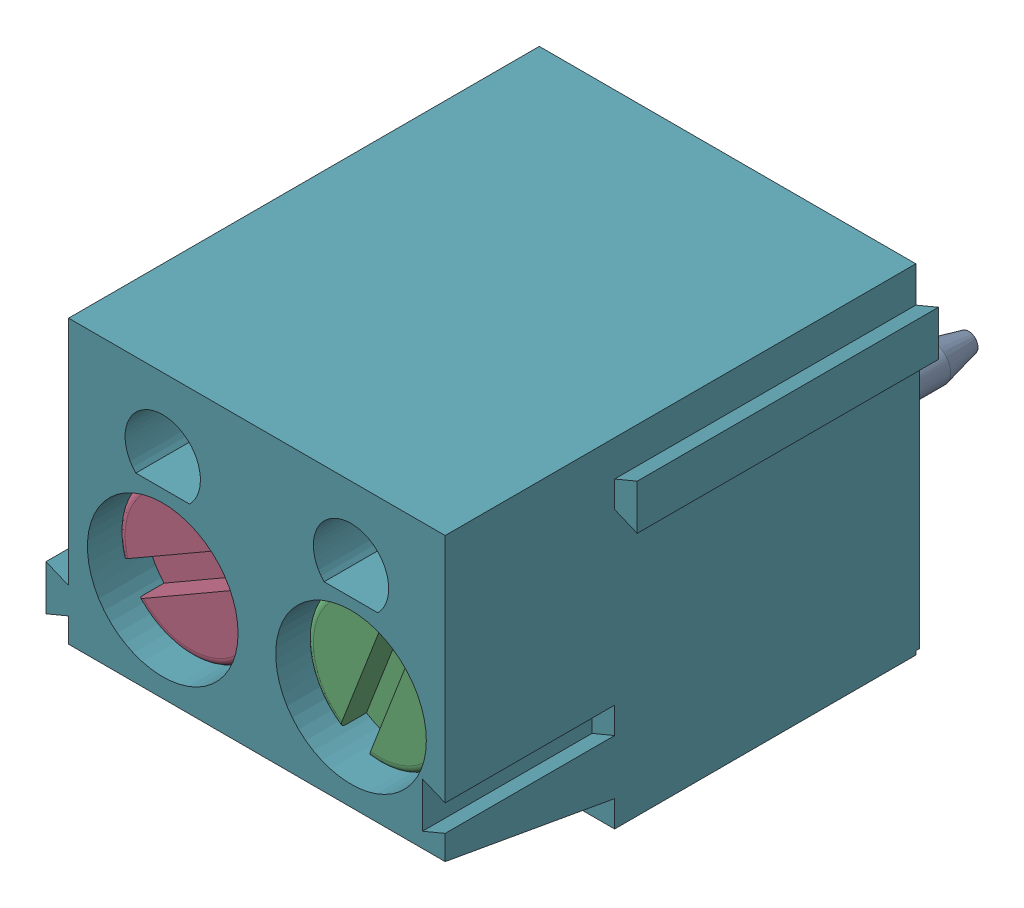
SolidWorks assembly 691101710002, configuration Default. Lengths in mm.
Overall size (11.2 9 16.4).
7 component instances, 4 part files, 0 mates.
Components (placement in the parent):
- 691101710002_1-1: 691101710002_1 [Default] at (2.5 0 4) size (3.95 4 10.9)
- 691101710002_1-2: 691101710002_1 [Default] at (-2.5 0 4) size (3.95 4 10.9)
- 691101710002_4-1: 691101710002_4 [Default] at (2.5 0.0307 11.75) x (0.93283 -0.360317 0) z (0 0 1) size (3.9 3.9 7.08)
- 691101710002_4-2: 691101710002_4 [Default] at (-2.5 0 11.75) x (0.5 -0.866025 0) z (0 0 1) size (3.9 3.9 7.08)
- 691101710002_2-1: 691101710002_2 [Default] at (2.5 0.0307 7.2) size (3.95 5.03 4.22)
- 691101710002_2-2: 691101710002_2 [Default] at (-2.5 0 7.2) size (3.95 5.03 4.22)
- 691101710002_3-1: 691101710002_3 [Default] at origin size (11.2 9 12.6)
